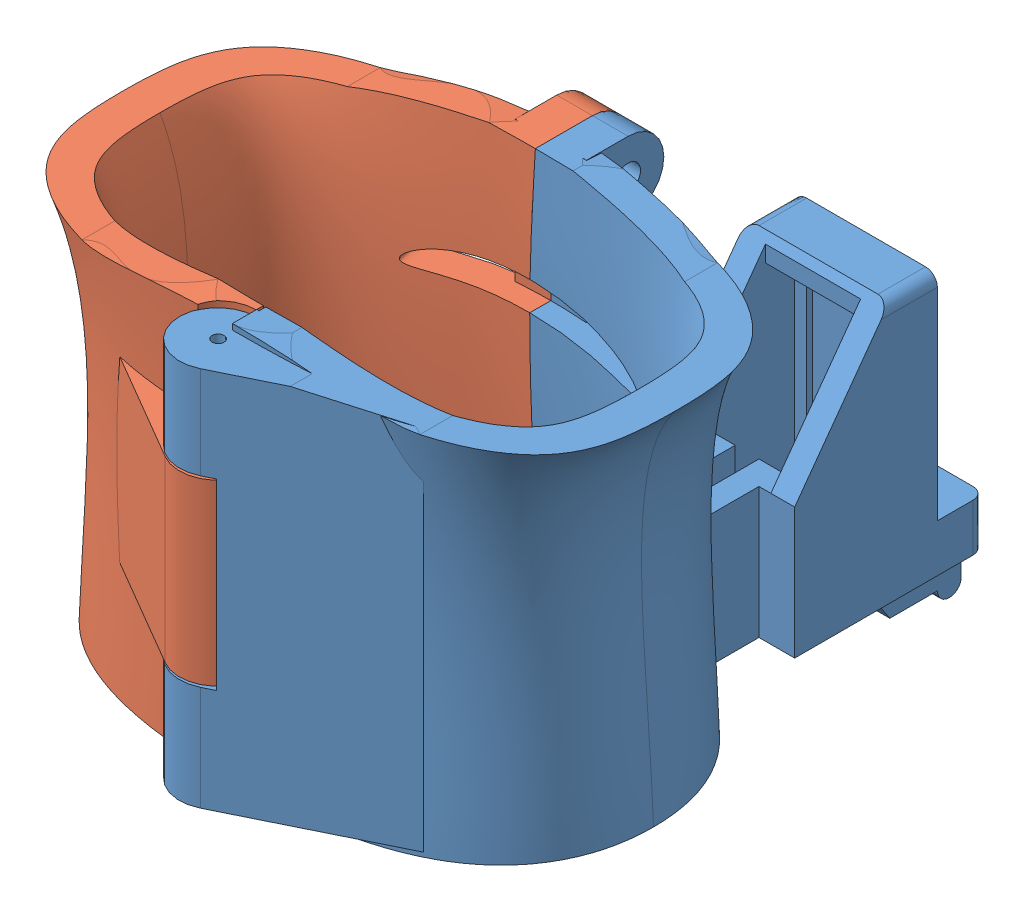
SolidWorks assembly Telemed-L12-FixtureConcept, configuration Default. Lengths in mm.
Overall size (58.34 35.26 48.72).
3 component instances, 3 part files, 1 mates.
Components (placement in the parent):
- Telemed-L12-Probe-1: Telemed-L12-Probe [Default] at (42.1476 116.703 122.4106) size (61.45 135.33 24.08) (hidden)
- TelemedHolder_L12_MarkedSide-1: TelemedHolder_L12_MarkedSide [Default] at (42.1476 116.7077 122.5105) size (32.42 35.25 48.72)
- TelemedHolder-L12_UnmarkedSide-1: TelemedHolder-L12_UnmarkedSide [Default] at (42.1476 116.7077 122.5105) size (32.42 35.26 37.72)
Mates (geometry in assembly coordinates):
- Concentric1: concentric anti-aligned: circle of TelemedHolder_L12_MarkedSide-1; circle of TelemedHolder-L12_UnmarkedSide-1
